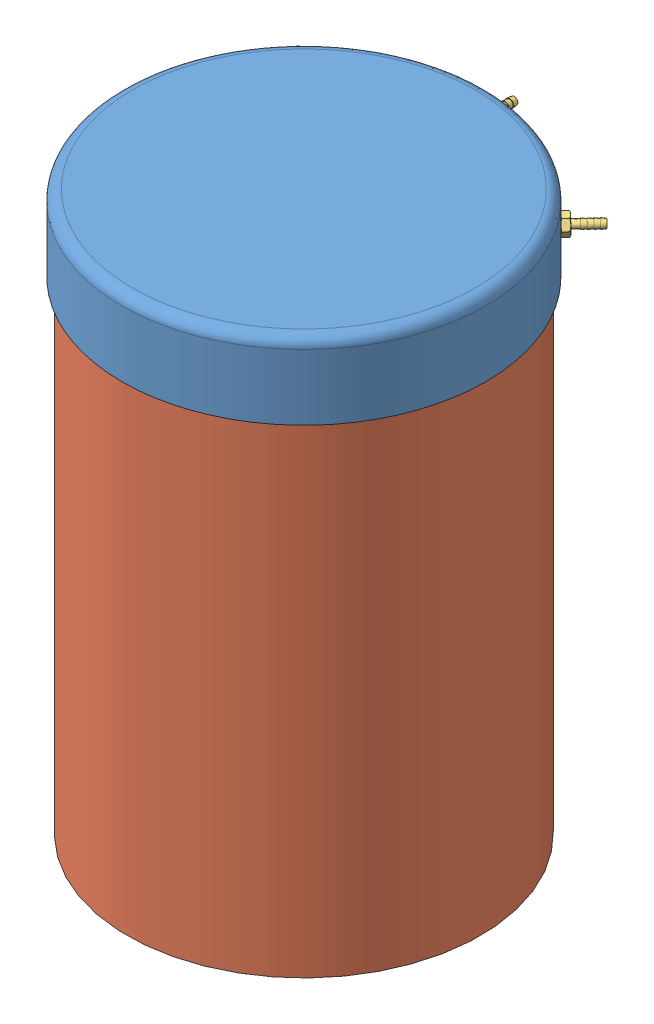
SolidWorks assembly Bottom assembly, configuration Default. Lengths in mm.
Overall size (457.9 512.76 457.9).
17 component instances, 7 part files, 45 mates.
Components (placement in the parent):
- 2051K124_CHEMICAL-RESISTANT PVC DUCT-1: 2051K124_CHEMICAL-RESISTANT PVC DUCT [2051K124] at (-8.1604 -60.8789 21.9388) size (333.77 69.85 333.77)
- PI-001-1: PI-001 [Default<As Machined>] at (-8.1604 -503.7914 21.9388) x (0.693013 0 -0.720925) z (-0.720925 0 -0.693013) size (323.85 508 323.85)
- 5372K112_DURABLE NYLON EXTRA-GRIP BARBED TUBE FITTING-1: 5372K112_DURABLE NYLON EXTRA-GRIP BARBED TUBE FITTING [5372K112] at (113.5188 -21.1914 -104.6413) x (0.693013 0 -0.720925) z (-0.624339 0.5 -0.600167) size (43.05 17.6 15.24)
- 5372K112_DURABLE NYLON EXTRA-GRIP BARBED TUBE FITTING-2: 5372K112_DURABLE NYLON EXTRA-GRIP BARBED TUBE FITTING [5372K112] at (-11.6267 -21.1914 -153.6505) x (-0.019737 0 -0.999805) z (0.865857 0.5 -0.017093) size (43.05 17.6 15.24)
- 4882K110_THICK-WALL DARK GRAY PVC THREADED PIPE NIPPLE-1: 4882K110_THICK-WALL DARK GRAY PVC THREADED PIPE NIPPLE [4882K11] at (-124.7915 -21.1914 -90.1766) x (-0.720925 0 -0.693013) z (0.026932 0.999245 -0.028016) size (22.92 14.28 14.5)
- 4882K110_THICK-WALL DARK GRAY PVC THREADED PIPE NIPPLE-2: 4882K110_THICK-WALL DARK GRAY PVC THREADED PIPE NIPPLE [4882K11] at (-124.7915 -478.3914 -90.1766) x (-0.720925 0 -0.693013) z (-0.121421 0.984531 0.126312) size (22.92 14.28 14.5)
- 5779K638_PUSH-TO-CONNECT TUBE FITTING FOR AIR-1: 5779K638_PUSH-TO-CONNECT TUBE FITTING FOR AIR [5779K638] at (-124.7915 -478.3914 -90.1766) x (-0.693013 0 0.720925) z (0.720925 0 0.693013) size (16 35.65 39.07)
- 5779K638_PUSH-TO-CONNECT TUBE FITTING FOR AIR-2: 5779K638_PUSH-TO-CONNECT TUBE FITTING FOR AIR [5779K638] at (-124.7915 -21.1914 -90.1766) x (0.693013 0 -0.720925) z (0.720925 0 0.693013) size (16 35.65 39.07)
- 5233K520_MASTERKLEER PVC TUBING-1: 5233K520_MASTERKLEER PVC TUBING [5233K52] at (-146.8568 -252.8394 -111.3877) x (0 1 0) z (0.000774 0 1) size (410.46 9.53 9.53)
- PI-004-1: PI-004 [Default<As Machined>] at (-8.4065 -97.3914 31.4606) x (0.958916 0 0.28369) z (-0.28369 0 0.958916) size (28.23 50.8 10.1)
- PI-004-2: PI-004 [Default<As Machined>] at (-4.6725 -97.3914 13.0754) x (-0.958916 0 -0.28369) z (0.28369 0 -0.958916) size (28.23 50.8 10.1)
- PI-004-3: PI-004 [Default<As Machined>] at (-17.4948 -97.3914 20.043) x (-0.28369 0 0.958916) z (-0.958916 0 -0.28369) size (28.23 50.8 10.1)
- PI-004-4: PI-004 [Default<As Machined>] at (1.174 -97.3914 23.8346) x (0.28369 0 -0.958916) z (0.958916 0 0.28369) size (28.23 50.8 10.1)
- PI-004-6: PI-004 [Default<As Machined>] at (-4.6725 -452.9914 13.0754) x (-0.958916 0 -0.28369) z (0.28369 0 -0.958916) size (28.23 50.8 10.1)
- PI-004-9: PI-004 [Default<As Machined>] at (-17.4948 -452.9914 20.043) x (-0.28369 0 0.958916) z (-0.958916 0 -0.28369) size (28.23 50.8 10.1)
- PI-004-13: PI-004 [Default<As Machined>] at (-8.4065 -452.9914 31.4606) x (0.958916 0 0.28369) z (-0.28369 0 0.958916) size (28.23 50.8 10.1)
- PI-004-14: PI-004 [Default<As Machined>] at (1.174 -452.9914 23.8346) x (0.28369 0 -0.958916) z (0.958916 0 0.28369) size (28.23 50.8 10.1)
Mates (geometry in assembly coordinates):
- Parallel1: parallel aligned: plane of PI-001-1 through (-8.1604 4.2086 21.9388) normal (0 1 0); plane of 5372K112_DURABLE NYLON EXTRA-GRIP BARBED TUBE FITTING-1 through (108.675 -13.5714 -105.9505) normal (0 1 0)
- Coincident4: coincident aligned: circle of 2051K124_CHEMICAL-RESISTANT PVC DUCT-1; plane of PI-001-1 through (-8.1604 4.2086 21.9388) normal (0 1 0)
- Concentric4: concentric aligned: cylinder of PI-001-1 through (104.0557 -21.1914 -94.797) axis (-0.693013 0 0.720925) radius 3.175; circle of 5372K112_DURABLE NYLON EXTRA-GRIP BARBED TUBE FITTING-1
- Concentric5: concentric anti-aligned: circle of 2051K124_CHEMICAL-RESISTANT PVC DUCT-1; circle of PI-001-1
- Concentric6: concentric aligned: cylinder of PI-001-1 through (-12.6801 -21.1914 -207.0131) axis (0.019737 0 0.999805) radius 3.175; circle of 5372K112_DURABLE NYLON EXTRA-GRIP BARBED TUBE FITTING-2
- Coincident5: coincident aligned: plane of 5372K112_DURABLE NYLON EXTRA-GRIP BARBED TUBE FITTING-1 through (115.0182 -28.8114 -99.8528) normal (0 -1 0); plane of 5372K112_DURABLE NYLON EXTRA-GRIP BARBED TUBE FITTING-2 through (-7.1805 -28.8114 -151.3248) normal (0 -1 0)
- Concentric7: concentric aligned: cylinder of PI-001-1 through (-124.8962 -21.1914 -90.2773) axis (0.720925 0 0.693013) radius 3.175; circle of 4882K110_THICK-WALL DARK GRAY PVC THREADED PIPE NIPPLE-1
- Tangent5: tangent: cylinder of PI-001-1 through (-8.1604 4.2086 21.9388) axis (0 -1 0) radius 161.925; circle of 4882K110_THICK-WALL DARK GRAY PVC THREADED PIPE NIPPLE-1
- Concentric10: concentric aligned: cylinder of PI-001-1 through (-124.8962 -478.3914 -90.2773) axis (0.720925 0 0.693013) radius 3.175; circle of 4882K110_THICK-WALL DARK GRAY PVC THREADED PIPE NIPPLE-2
- Tangent6: tangent: cylinder of PI-001-1 through (-8.1604 4.2086 21.9388) axis (0 -1 0) radius 161.925; circle of 4882K110_THICK-WALL DARK GRAY PVC THREADED PIPE NIPPLE-2
- Concentric11: concentric aligned: circle of 4882K110_THICK-WALL DARK GRAY PVC THREADED PIPE NIPPLE-2; circle of 5779K638_PUSH-TO-CONNECT TUBE FITTING FOR AIR-1
- Coincident6: coincident aligned: circle of 4882K110_THICK-WALL DARK GRAY PVC THREADED PIPE NIPPLE-2; plane of 5779K638_PUSH-TO-CONNECT TUBE FITTING FOR AIR-1 through (-124.7915 -478.3914 -90.1766) normal (0.720925 0 0.693013)
- Concentric12: concentric aligned: circle of 4882K110_THICK-WALL DARK GRAY PVC THREADED PIPE NIPPLE-1; circle of 5779K638_PUSH-TO-CONNECT TUBE FITTING FOR AIR-2
- Coincident7: coincident aligned: circle of 4882K110_THICK-WALL DARK GRAY PVC THREADED PIPE NIPPLE-2; plane of 5779K638_PUSH-TO-CONNECT TUBE FITTING FOR AIR-2 through (-124.7915 -21.1914 -90.1766) normal (0.720925 0 0.693013)
- Parallel3: parallel anti-aligned: plane of 5779K638_PUSH-TO-CONNECT TUBE FITTING FOR AIR-1 through (-142.0317 -451.9754 -106.7494) normal (0 1 0); plane of 5779K638_PUSH-TO-CONNECT TUBE FITTING FOR AIR-2 through (-142.0317 -47.6074 -106.7494) normal (0 -1 0)
- Parallel4: parallel aligned: plane of PI-001-1 through (-8.1604 -503.7914 21.9388) normal (0 -1 0); plane of 5779K638_PUSH-TO-CONNECT TUBE FITTING FOR AIR-2 through (-142.0317 -47.6074 -106.7494) normal (0 -1 0)
- Concentric13: concentric anti-aligned: circle of 5779K638_PUSH-TO-CONNECT TUBE FITTING FOR AIR-2; cylinder of 5233K520_MASTERKLEER PVC TUBING-1 through (-146.8568 -47.6074 -111.3877) axis (0 -1 0) radius 4.7625
- Coincident11: coincident anti-aligned: plane of 5779K638_PUSH-TO-CONNECT TUBE FITTING FOR AIR-2 through (-142.0317 -47.6074 -106.7494) normal (0 -1 0); plane of 5233K520_MASTERKLEER PVC TUBING-1 through (-146.8568 -47.6074 -111.3877) normal (0 1 0)
- Coincident12: coincident: point of 2051K124_CHEMICAL-RESISTANT PVC DUCT-1; moEndPointRef_w of 5372K112_DURABLE NYLON EXTRA-GRIP BARBED TUBE FITTING-1
- Tangent8: tangent anti-aligned: cylinder of 2051K124_CHEMICAL-RESISTANT PVC DUCT-1 through (-8.1604 -60.8789 21.9388) axis (0 -1 0) radius 166.8859; plane of 5372K112_DURABLE NYLON EXTRA-GRIP BARBED TUBE FITTING-2 through (-20.2513 -21.1914 -144.741) normal (0.019737 0 0.999805)
- Tangent9: tangent aligned: cylinder of PI-001-1 through (-8.1604 4.2086 21.9388) axis (0 -1 0) radius 152.4; cylinder of PI-004-1 through (-8.4065 -46.5914 31.4606) axis (0 -1 0) radius 161.925
- Distance1: distance = 50.8 mm aligned: plane of PI-004-1 through (-8.4065 -46.5914 31.4606) normal (0 1 0); plane of PI-001-1 through (-8.1604 4.2086 21.9388) normal (0 1 0)
- Tangent10: tangent aligned: cylinder of PI-001-1 through (-8.1604 4.2086 21.9388) axis (0 -1 0) radius 152.4; cylinder of PI-004-2 through (-4.6725 -46.5914 13.0754) axis (0 -1 0) radius 161.925
- Coincident16: coincident aligned: plane of PI-004-1 through (-8.4065 -46.5914 31.4606) normal (0 1 0); plane of PI-004-2 through (-4.6725 -46.5914 13.0754) normal (0 1 0)
- Coincident20: coincident anti-aligned: plane of PI-004-1 through (-8.4065 -97.3914 31.4606) normal (-0.979992 0 -0.199035); plane of PI-004-2 through (-4.6725 -97.3914 13.0754) normal (0.979992 0 0.199035)
- Coincident21: coincident aligned: plane of PI-004-2 through (-4.6725 -97.3914 13.0754) normal (0 -1 0); plane of PI-004-3 through (-17.4948 -97.3914 20.043) normal (0 -1 0)
- Tangent11: tangent aligned: cylinder of PI-001-1 through (-8.1604 4.2086 21.9388) axis (0 -1 0) radius 152.4; cylinder of PI-004-3 through (-17.4948 -46.5914 20.043) axis (0 -1 0) radius 161.925
- Angle1: planar angle = 1.570796 rad aligned: plane of PI-004-3 through (-17.4948 -97.3914 20.043) normal (0.199035 0 -0.979992); plane of PI-004-2 through (-4.6725 -97.3914 13.0754) normal (0.979992 0 0.199035)
- Coincident23: coincident aligned: plane of PI-004-2 through (-4.6725 -97.3914 13.0754) normal (0 -1 0); plane of PI-004-4 through (1.174 -97.3914 23.8346) normal (0 -1 0)
- Coincident25: coincident anti-aligned: plane of PI-004-3 through (-17.4948 -97.3914 20.043) normal (0.199035 0 -0.979992); plane of PI-004-4 through (1.174 -97.3914 23.8346) normal (-0.199035 0 0.979992)
- Tangent13: tangent aligned: cylinder of PI-001-1 through (-8.1604 4.2086 21.9388) axis (0 -1 0) radius 152.4; cylinder of PI-004-4 through (1.174 -46.5914 23.8346) axis (0 -1 0) radius 161.925
- Coincident27: coincident: cylinder of PI-001-1 through (-8.1604 4.2086 21.9388) axis (0 -1 0) radius 152.4; point of PI-004-2
- Tangent15: tangent aligned: cylinder of PI-001-1 through (-8.1604 4.2086 21.9388) axis (0 -1 0) radius 152.4; cylinder of PI-004-6 through (-4.6725 -402.1914 13.0754) axis (0 -1 0) radius 161.925
- Coincident28: coincident aligned: plane of PI-004-2 through (-4.6725 -97.3914 13.0754) normal (-0.930542 0 -0.366185); plane of PI-004-6 through (-4.6725 -452.9914 13.0754) normal (-0.930542 0 -0.366185)
- Distance4: distance = 50.8 mm aligned: plane of PI-004-6 through (-4.6725 -452.9914 13.0754) normal (0 -1 0); plane of PI-001-1 through (-8.1604 -503.7914 21.9388) normal (0 -1 0)
- Coincident31: coincident: cylinder of PI-001-1 through (-8.1604 4.2086 21.9388) axis (0 -1 0) radius 152.4; point of PI-004-3
- Tangent18: tangent aligned: cylinder of PI-001-1 through (-8.1604 4.2086 21.9388) axis (0 -1 0) radius 152.4; cylinder of PI-004-9 through (-17.4948 -402.1914 20.043) axis (0 -1 0) radius 161.925
- Coincident32: coincident aligned: plane of PI-004-3 through (-17.4948 -97.3914 20.043) normal (-0.366185 0 0.930542); plane of PI-004-9 through (-17.4948 -452.9914 20.043) normal (-0.366185 0 0.930542)
- Distance7: distance = 50.8 mm aligned: plane of PI-004-9 through (-17.4948 -452.9914 20.043) normal (0 -1 0); plane of PI-001-1 through (-8.1604 -503.7914 21.9388) normal (0 -1 0)
- Tangent22: tangent aligned: cylinder of PI-001-1 through (-8.1604 4.2086 21.9388) axis (0 -1 0) radius 152.4; cylinder of PI-004-13 through (-8.4065 -402.1914 31.4606) axis (0 -1 0) radius 161.925
- Coincident37: coincident aligned: plane of PI-004-1 through (-8.4065 -97.3914 31.4606) normal (0.930542 0 0.366185); plane of PI-004-13 through (-8.4065 -452.9914 31.4606) normal (0.930542 0 0.366185)
- Distance11: distance = 50.8 mm aligned: plane of PI-004-13 through (-8.4065 -452.9914 31.4606) normal (0 -1 0); plane of PI-001-1 through (-8.1604 -503.7914 21.9388) normal (0 -1 0)
- Tangent23: tangent aligned: cylinder of PI-001-1 through (-8.1604 4.2086 21.9388) axis (0 -1 0) radius 152.4; cylinder of PI-004-14 through (1.174 -402.1914 23.8346) axis (0 -1 0) radius 161.925
- Distance12: distance = 50.8 mm aligned: plane of PI-001-1 through (-8.1604 -503.7914 21.9388) normal (0 -1 0); plane of PI-004-14 through (1.174 -452.9914 23.8346) normal (0 -1 0)
- Coincident41: coincident aligned: plane of PI-004-4 through (1.174 -97.3914 23.8346) normal (0.366185 0 -0.930542); plane of PI-004-14 through (1.174 -452.9914 23.8346) normal (0.366185 0 -0.930542)
